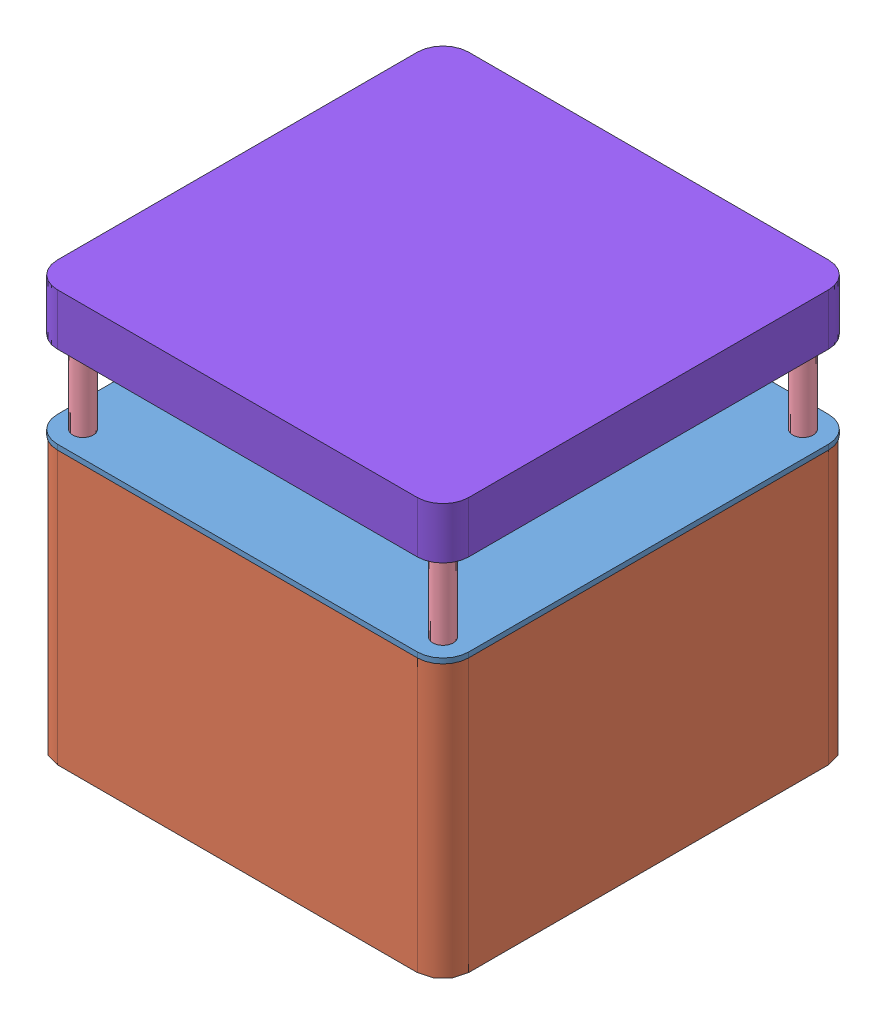
SolidWorks assembly balise, configuration Default. Lengths in mm.
Overall size (80 80 80).
12 component instances, 9 part files, 23 mates.
Components (placement in the parent):
- Couvercle-1: Couvercle [Default] at (-41.2383 17.8902 27.5538) size (80 1 80)
- boite-1: boite [Default] at (38.7617 -35.1098 -52.4462) x (-1 0 0) z (0 0 -1) size (80 53 80)
- Moteur-1: Moteur [Default] at (-1.2383 -22.1098 -12.4462) size (30 47 30)
- tige-1: tige [Default] at (-36.2383 34.8902 -47.4462) x (-0.837169 0 -0.546944) z (-0.546944 0 0.837169) size (4 16 4)
- tige-2: tige [Default] at (-36.2383 34.8902 22.5538) x (-0.837169 0 -0.546944) z (-0.546944 0 0.837169) size (4 16 4)
- tige-3: tige [Default] at (33.7617 34.8902 22.5538) x (-0.837169 0 -0.546944) z (-0.546944 0 0.837169) size (4 16 4)
- tige-4: tige [Default] at (33.7617 34.8902 -47.4462) x (-0.837169 0 -0.546944) z (-0.546944 0 0.837169) size (4 16 4)
- MiroirTournant-1: MiroirTournant [Default] at (-10.8187 19.8902 -9.9528) x (0.506213 0 -0.862408) z (0.862408 0 0.506213) size (14 14 14)
- SupportLaser2-1: SupportLaser2 [Default] at (-39.2383 17.8902 -21.4462) x (0 -1 0) z (-1 0 0) size (10 18 13)
- Laser-1: Laser [Default] at (-33.7383 -22.1098 -12.4462) x (0.707107 0 0.707107) z (0 1 0) size (10 10 40)
- boiteHautMoule-1: boiteHautMoule [Défaut] at (-41.2383 34.8902 27.5538) size (80 10 80)
- Led-1: Led [Défaut] at (4.708 39.8902 -12.3841) x (-0.999565 0 -0.029497) z (-0.029497 0 0.999565) size (5 5 5)
Mates (geometry in assembly coordinates):
- Coïncidente4: coincident: circle of Couvercle-1; circle of Moteur-1
- Coïncidente8: coincident: plane of Couvercle-1 through (-41.2383 18.8902 -52.4462) normal (0 1 0); plane of tige-2 through (-36.2383 18.8902 22.5538) normal (0 -1 0)
- Coaxiale1: concentric: circle of Couvercle-1; circle of tige-2
- Coïncidente9: coincident: plane of Couvercle-1 through (-41.2383 18.8902 -52.4462) normal (0 1 0); plane of tige-1 through (-36.2383 18.8902 -47.4462) normal (0 -1 0)
- Coïncidente10: coincident: plane of Couvercle-1 through (-41.2383 18.8902 -52.4462) normal (0 1 0); plane of tige-3 through (33.7617 18.8902 22.5538) normal (0 -1 0)
- Coïncidente11: coincident: plane of Couvercle-1 through (-41.2383 18.8902 -52.4462) normal (0 1 0); plane of tige-4 through (33.7617 18.8902 -47.4462) normal (0 -1 0)
- Coaxiale2: concentric: circle of Couvercle-1; circle of tige-1
- Coaxiale3: concentric: circle of Couvercle-1; circle of tige-4
- Coaxiale5: concentric: circle of Couvercle-1; circle of tige-3
- Coaxiale6: concentric: circle of Moteur-1; circle of ?
- Distance4: distance = 1 mm: plane of Couvercle-1 through (-41.2383 18.8902 -52.4462) normal (0 1 0); plane of MiroirTournant-1 through (1.255 19.8902 -2.8658) normal (0 -1 0)
- Coaxiale9: concentric: cylinder of ?; cylinder of ?
- Coïncidente22: coincident: plane of boiteHautMoule-1 through (2.7617 39.8902 -14.9462) normal (0 -1 0); plane of Led-1 through (4.708 39.8902 -12.3841) normal (0 1 0)
- Coïncidente25: coincident: moEndPointRef_w of boiteHautMoule-1; circle of Led-1
- Coaxiale15: concentric: circle of tige-3; circle of boiteHautMoule-1
- Coaxiale16: concentric: circle of tige-4; circle of boiteHautMoule-1
- Coïncidente26: coincident: plane of tige-3 through (33.7617 34.8902 22.5538) normal (0 1 0); plane of boiteHautMoule-1 through (-41.2383 34.8902 -52.4462) normal (0 -1 0)
- Coïncidente27: coincident: plane of ? through (-39.2383 17.8902 -3.4462) normal (0 -1 0); plane of ? through (-44.7383 17.8902 -12.4462) normal (0 -1 0)
- Coïncidente42: coincident: plane of Couvercle-1 through (-41.2383 17.8902 -52.4462) normal (0 -1 0); plane of boite-1 through (38.7617 17.8902 27.5538) normal (0 1 0)
- Coïncidente45: coincident: line of Couvercle-1; line of boite-1
- Coïncidente46: coincident: line of Couvercle-1; line of boite-1
- Coïncidente47: coincident: line of boite-1; line of ?
- Distance10: distance = 31 mm: line of boite-1; line of SupportLaser2-1
